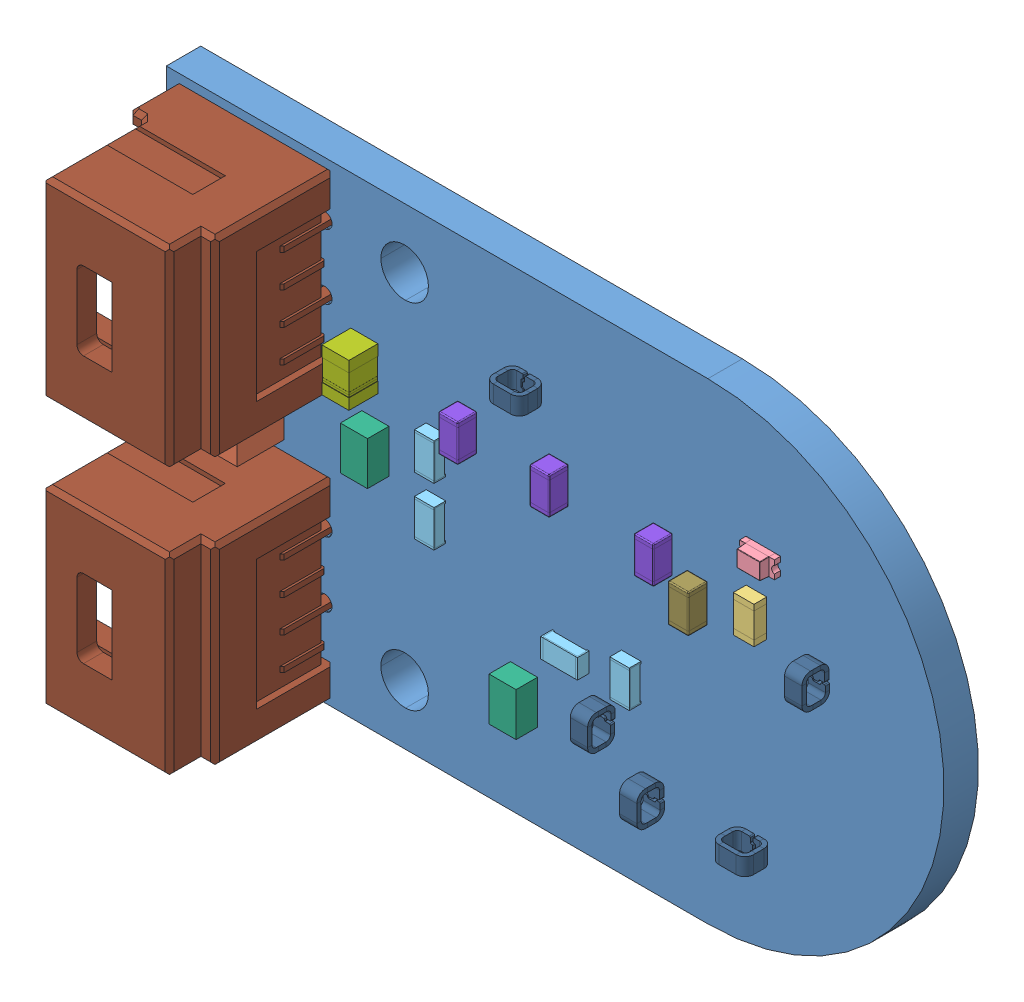
SolidWorks assembly Encoder_Board_REV_A, configuration Default. Lengths in mm.
Overall size (35.9 21.8 10.35).
23 component instances, 12 part files, 0 mates.
Components (placement in the parent):
- Encoder_Board_REV_A_BOARD-1: Encoder_Board_REV_A_BOARD [Default] at origin size (35.9 21.8 1.59)
- ONSC-SMA-2-403D-02_F_V_CMP-004-00038-1-1: ONSC-SMA-2-403D-02_F_V_CMP-004-00038-1 [Default] at (26.302 90 1.58) size (4.32 2.6 2.15)
- RESC0603(1608)_N_CMP-009-00178-1-1: RESC0603(1608)_N_CMP-009-00178-1 [Default] at (50.241 92.6811 1.58) x (0 1 0) z (0 0 1) size (1.7 0.95 0.6)
- WL-SMCW_0603_150060xx75000_CMP-007-00036-1-1: WL-SMCW_0603_150060xx75000_CMP-007-00036-1 [Default] at (50.559 95.08 1.58) size (1.6 0.8 0.7)
- RESC1608X55X25NL10T15_CMP-009-00017-7-1: RESC1608X55X25NL10T15_CMP-009-00017-7 [Default] at (35.446 89.111 1.58) x (0 -1 0) z (0 0 1) size (1.7 0.9 0.55)
- RESC1608X55X25NL10T15_CMP-009-00017-7-2: RESC1608X55X25NL10T15_CMP-009-00017-7 [Default] at (35.446 91.778 1.58) x (0 1 0) z (0 0 1) size (1.7 0.9 0.55)
- RESC1608X55X25NL10T15_CMP-009-00017-7-3: RESC1608X55X25NL10T15_CMP-009-00017-7 [Default] at (41.669 86.825 1.58) size (1.7 0.9 0.55)
- RESC1608X55X25NL10T15_CMP-009-00017-7-4: RESC1608X55X25NL10T15_CMP-009-00017-7 [Default] at (44.463 87.206 1.58) x (0 1 0) z (0 0 1) size (1.7 0.9 0.55)
- ONSC-SC-70-3-419-04_V_CMP-004-00039-1-1: ONSC-SC-70-3-419-04_V_CMP-004-00039-1 [Default] at (39.51 84.031 1.58) size (1.25 2 1)
- ONSC-SC-70-3-419-04_V_CMP-004-00039-1-2: ONSC-SC-70-3-419-04_V_CMP-004-00039-1 [Default] at (32.652 90.635 1.58) x (-1 0 0) z (0 0 1) size (1.25 2 1)
- CAP_CER_10UF_16V_X5R_0805-Footprint-1_CMP-001-00084-6-1: CAP_CER_10UF_16V_X5R_0805-Footprint-1_CMP-001-00084-6 [Default] at (32.144 93.683 1.58) x (0 1 0) z (0 0 1) size (2 1.25 1.35)
- CAPC1608X90X40NL10T20_CMP-001-00017-8-1: CAPC1608X90X40NL10T20_CMP-001-00017-8 [Default] at (36.8938 93.4036 1.58) x (0 -1 0) z (0 0 1) size (1.7 0.9 0.9)
- CAPC1608X90X40NL10T20_CMP-001-00017-8-2: CAPC1608X90X40NL10T20_CMP-001-00017-8 [Default] at (41.1102 93.4036 1.58) x (0 -1 0) z (0 0 1) size (1.7 0.9 0.9)
- CAPC1608X90X40NL10T20_CMP-001-00017-8-3: CAPC1608X90X40NL10T20_CMP-001-00017-8 [Default] at (45.923 93.0484 1.58) x (0 1 0) z (0 0 1) size (1.7 0.9 0.9)
- AS5600L-ASOM-Footprint-1_CMP-010-00024-5-1: AS5600L-ASOM-Footprint-1_CMP-010-00024-5 [Default] at (48 90 0.01) x (0 -1 0) z (0 0 -1) size (6 4.91 1.76)
- FP-S2761-46R-MFG_CMP-002-00072-5-1: FP-S2761-46R-MFG_CMP-002-00072-5 [Default] at (43.32 85.047 1.58) x (0 1 0) z (0 0 1) size (1.6 0.8 1.28)
- FP-S2761-46R-MFG_CMP-002-00072-5-2: FP-S2761-46R-MFG_CMP-002-00072-5 [Default] at (50.178 83.396 1.58) size (1.6 0.8 1.28)
- FP-S2761-46R-MFG_CMP-002-00072-5-3: FP-S2761-46R-MFG_CMP-002-00072-5 [Default] at (45.591 83.142 1.58) x (0 -1 0) z (0 0 1) size (1.6 0.8 1.28)
- FP-S2761-46R-MFG_CMP-002-00072-5-4: FP-S2761-46R-MFG_CMP-002-00072-5 [Default] at (39.764 96.604 1.58) x (-1 0 0) z (0 0 1) size (1.6 0.8 1.28)
- FP-S2761-46R-MFG_CMP-002-00072-5-5: FP-S2761-46R-MFG_CMP-002-00072-5 [Default] at (53.211 91.651 1.58) x (0 -1 0) z (0 0 1) size (1.6 0.8 1.28)
- 5031750400-Footprint-1_CMP-002-00074-2-1: 5031750400-Footprint-1_CMP-002-00074-2 [Default] at (30.3 98.4 1.58) x (0 -1 0) z (0 0 1) size (8.9 7.25 10.35)
- 5031750400-Footprint-1_CMP-002-00074-2-2: 5031750400-Footprint-1_CMP-002-00074-2 [Default] at (30.3 86.1 1.58) x (0 -1 0) z (0 0 1) size (8.9 7.25 10.35)
- CAPC1608X90X35NL15T15_CMP-001-00004-8-1: CAPC1608X90X35NL15T15_CMP-001-00004-8 [Default] at (47.511 91.905 1.58) x (0 1 0) z (0 0 1) size (1.75 0.95 0.9)
